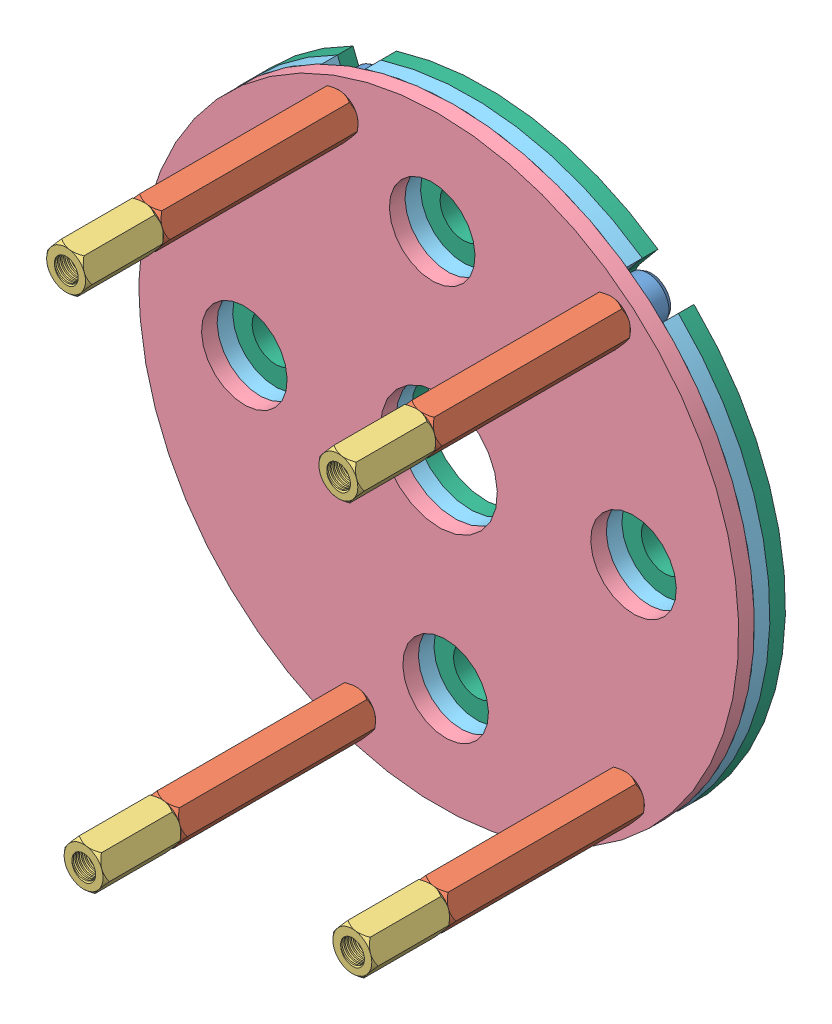
SolidWorks assembly FlangeAX12, configuration Default. Lengths in mm.
Overall size (79.61 79.61 41.15).
15 component instances, 6 part files, 30 mates.
Components (placement in the parent):
- M3x10-1: M3x10 [Default] at (-1559.277 1455.5839 1401.6256) x (0.911881 0.410454 0) z (-0.410454 0.911881 0) size (5.5 13.21 5.5)
- M3x10-2: M3x10 [Default] at (-1522.5204 1398.1902 1401.6256) x (-0.081495 -0.996674 0) z (0.996674 -0.081495 0) size (5.5 13.21 5.5)
- M3x10-3: M3x10 [Default] at (-1557.0273 1390.3304 1401.6256) x (0.009393 0.999956 0) z (-0.999956 0.009393 0) size (5.5 13.21 5.5)
- M3x10-4: M3x10 [Default] at (-1524.3108 1450.1194 1401.6256) x (-0.968317 0.249723 0) z (-0.249723 -0.968317 0) size (5.5 13.21 5.5)
- M3Spacer25-1: M3Spacer25 [Default] at (-1522.5204 1398.1902 1403.6256) x (-0.353582 0.935404 0) z (0.935404 0.353582 0) size (6.28 25.53 5)
- M3Spacer25-2: M3Spacer25 [Default] at (-1557.0273 1390.3304 1403.6256) x (-0.353582 0.935404 0) z (0.935404 0.353582 0) size (6.28 25.53 5)
- M3Spacer25-3: M3Spacer25 [Default] at (-1559.277 1455.5839 1403.6256) x (-0.353582 0.935404 0) z (0.935404 0.353582 0) size (6.28 25.53 5)
- M3Spacer25-4: M3Spacer25 [Default] at (-1524.3108 1450.1194 1403.6256) x (-0.353582 0.935404 0) z (0.935404 0.353582 0) size (6.28 25.53 5)
- M3Spacer10-1: M3Spacer10 [Default] at (-1522.5204 1398.1902 1438.6256) x (-0.353582 0.935404 0) z (-0.935404 -0.353582 0) size (6.28 16.65 5)
- M3Spacer10-2: M3Spacer10 [Default] at (-1557.0273 1390.3304 1438.6256) x (-0.353582 0.935404 0) z (-0.935404 -0.353582 0) size (6.28 16.65 5)
- M3Spacer10-3: M3Spacer10 [Default] at (-1559.277 1455.5839 1438.6256) x (-0.353582 0.935404 0) z (-0.935404 -0.353582 0) size (6.28 16.65 5)
- M3Spacer10-4: M3Spacer10 [Default] at (-1524.3108 1450.1194 1438.6256) x (-0.353582 0.935404 0) z (-0.935404 -0.353582 0) size (6.28 16.65 5)
- flangeAX12_1-2: flangeAX12_1 [Default] at (-1546.402 1423.3623 1403.6256) x (-0.999406 -0.034457 0) z (0 0 -1) size (77 77 2)
- flangeAX12_2-1: flangeAX12_2 [Default] at (-1546.402 1423.3623 1401.6256) x (-0.999406 -0.034457 0) z (0 0 -1) size (77 77 2)
- flangeAX12_3-1: flangeAX12_3 [Default] at (-1546.402 1423.3623 1399.6256) x (-0.999406 -0.034457 0) z (0 0 -1) size (77 77 2)
Mates (geometry in assembly coordinates):
- Concentric10: concentric anti-aligned: circle of M3Spacer25-4; circle of M3Spacer10-4
- Concentric12: concentric anti-aligned: circle of M3Spacer25-3; circle of M3Spacer10-3
- Concentric14: concentric anti-aligned: circle of M3Spacer25-2; circle of M3Spacer10-2
- Concentric16: concentric anti-aligned: circle of M3Spacer25-1; circle of M3Spacer10-1
- Coincident13: coincident anti-aligned: plane of M3Spacer25-3 through (-1559.277 1455.5839 1428.6256) normal (0 0 1); plane of M3Spacer10-3 through (-1559.277 1455.5839 1428.6256) normal (0 0 -1)
- Coincident14: coincident anti-aligned: plane of M3Spacer25-4 through (-1491.1961 1474.244 1428.6256) normal (0 0 1); plane of M3Spacer10-4 through (-1491.1961 1474.244 1428.6256) normal (0 0 -1)
- Coincident15: coincident anti-aligned: plane of M3Spacer25-1 through (-1482.407 1409.8072 1428.6256) normal (0 0 1); plane of M3Spacer10-1 through (-1482.407 1409.8072 1428.6256) normal (0 0 -1)
- Coincident16: coincident anti-aligned: plane of M3Spacer25-2 through (-1557.0273 1390.3304 1428.6256) normal (0 0 1); plane of M3Spacer10-2 through (-1557.0273 1390.3304 1428.6256) normal (0 0 -1)
- Concentric17: concentric aligned: circle of flangeAX12_1-2; circle of flangeAX12_2-1
- Concentric18: concentric aligned: circle of flangeAX12_1-2; circle of flangeAX12_3-1
- Coincident18: coincident anti-aligned: plane of flangeAX12_1-2 through (-1546.402 1423.3623 1401.6256) normal (0 0 -1); plane of flangeAX12_2-1 through (-1546.402 1423.3623 1401.6256) normal (0 0 1)
- Coincident19: coincident anti-aligned: plane of flangeAX12_2-1 through (-1546.402 1423.3623 1399.6256) normal (0 0 -1); plane of flangeAX12_3-1 through (-1546.402 1423.3623 1399.6256) normal (0 0 1)
- Concentric24: concentric aligned: circle of M3x10-3; circle of flangeAX12_1-2
- Concentric27: concentric aligned: circle of M3x10-1; circle of flangeAX12_1-2
- Concentric28: concentric aligned: circle of M3Spacer10-2; circle of flangeAX12_1-2
- Concentric31: concentric aligned: circle of M3Spacer10-3; circle of flangeAX12_1-2
- Coincident20: coincident anti-aligned: plane of M3Spacer25-3 through (-1559.277 1455.5839 1403.6256) normal (0 0 -1); plane of flangeAX12_1-2 through (-1546.402 1423.3623 1403.6256) normal (0 0 1)
- Coincident21: coincident anti-aligned: plane of M3x10-1 through (-1559.277 1455.5839 1401.6256) normal (0 0 1); plane of flangeAX12_1-2 through (-1546.402 1423.3623 1401.6256) normal (0 0 -1)
- Coincident22: coincident anti-aligned: plane of M3Spacer25-4 through (-1491.1961 1474.244 1403.6256) normal (0 0 -1); plane of flangeAX12_1-2 through (-1546.402 1423.3623 1403.6256) normal (0 0 1)
- Coincident23: coincident: plane of M3x10-4 through (-1524.3108 1450.1194 1401.6256) normal (0 0 1); plane of flangeAX12_1-2 through (-1546.402 1423.3623 1401.6256) normal (0 0 -1)
- Coincident24: coincident anti-aligned: plane of M3Spacer25-1 through (-1482.407 1409.8072 1403.6256) normal (0 0 -1); plane of flangeAX12_1-2 through (-1546.402 1423.3623 1403.6256) normal (0 0 1)
- Coincident25: coincident: plane of M3x10-2 through (-1522.5204 1398.1902 1401.6256) normal (0 0 1); plane of flangeAX12_1-2 through (-1546.402 1423.3623 1401.6256) normal (0 0 -1)
- Coincident26: coincident anti-aligned: plane of M3Spacer25-2 through (-1557.0273 1390.3304 1403.6256) normal (0 0 -1); plane of flangeAX12_1-2 through (-1546.402 1423.3623 1403.6256) normal (0 0 1)
- Coincident27: coincident anti-aligned: plane of M3x10-3 through (-1557.0273 1390.3304 1401.6256) normal (0 0 1); plane of flangeAX12_1-2 through (-1546.402 1423.3623 1401.6256) normal (0 0 -1)
- Concentric32: concentric aligned: circle of flangeAX12_1-2; circle of flangeAX12_3-1
- Concentric33: concentric aligned: circle of flangeAX12_1-2; circle of flangeAX12_2-1
- Concentric34: concentric aligned: circle of M3x10-4; circle of flangeAX12_1-2
- Concentric35: concentric anti-aligned: circle of M3x10-4; circle of M3Spacer25-4
- Concentric36: concentric aligned: circle of M3x10-2; circle of flangeAX12_1-2
- Concentric37: concentric anti-aligned: circle of M3x10-2; circle of M3Spacer25-1
